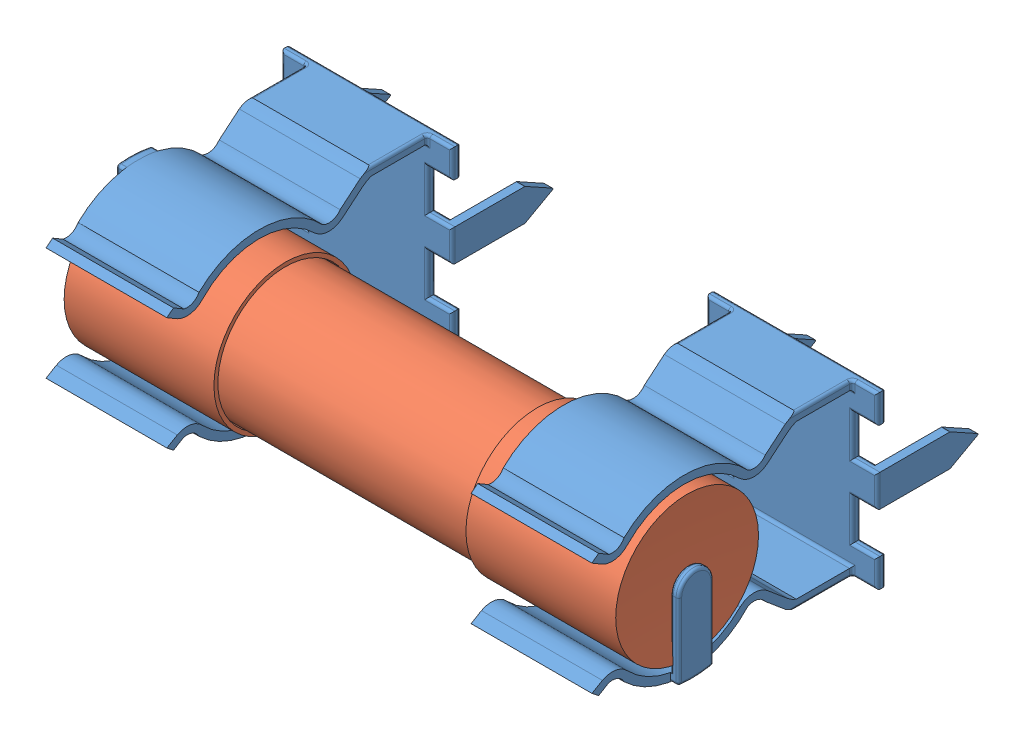
SolidWorks assembly User Library-Full Fuse, configuration Default. Lengths in mm.
Overall size (21.28 6.19 12.9).
3 component instances, 2 part files, 5 mates.
Components (placement in the parent):
- User Library-Full Fuse_Fuse Leg_2009-1: User Library-Full Fuse_Fuse Leg_2009 [Default] at (4.6924 0.7804 -3.0063) size (6.1 6.19 12.9)
- User Library-Full Fuse_Fuse Leg_2009-2: User Library-Full Fuse_Fuse Leg_2009 [Default] at (-10.4896 0.7804 -3.0063) x (-1 0 0) z (0 0 1) size (6.1 6.19 12.9)
- User Library-Full Fuse_Fuse Small 1A-1: User Library-Full Fuse_Fuse Small 1A [Default] at (-2.8986 0.7804 3.2937) size (19.7 5.1 5.1)
Mates (geometry in assembly coordinates):
- Tangent1: tangent: plane of User Library-Full Fuse_Fuse Leg_2009-1 through (6.8514 1.2513 3.3137) normal (-1 0 0); sphere of User Library-Full Fuse_Fuse Small 1A-1
- Tangent2: tangent: plane of User Library-Full Fuse_Fuse Leg_2009-2 through (-12.6486 0.3095 3.3137) normal (1 0 0); sphere of User Library-Full Fuse_Fuse Small 1A-1
- Coincident1: coincident: plane of User Library-Full Fuse_Fuse Leg_2009-1 through (1.6444 3.8284 -2.7063) normal (0 1 0); plane of User Library-Full Fuse_Fuse Leg_2009-2 through (-7.4416 3.8284 -2.7063) normal (0 1 0)
- Coincident2: coincident: plane of User Library-Full Fuse_Fuse Leg_2009-1 through (7.7404 3.8284 -3.0063) normal (0 0 -1); plane of User Library-Full Fuse_Fuse Leg_2009-2 through (-13.5376 -2.2676 -3.0063) normal (0 0 -1)
- Concentric1: concentric: cylinder of User Library-Full Fuse_Fuse Leg_2009-1 through (2.5334 0.7804 3.2937) axis (1 0 0) radius 2.814; cylinder of User Library-Full Fuse_Fuse Small 1A-1 through (6.9514 0.7804 3.2937) axis (-1 0 0) radius 2.55
